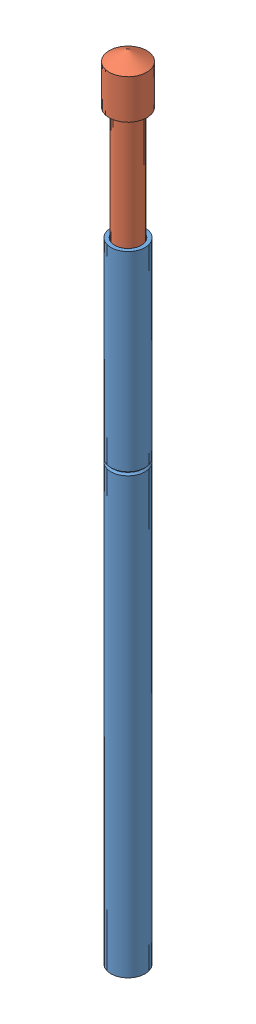
SolidWorks assembly Pin Assembly, configuration Default. Lengths in mm.
Overall size (1.57 31.69 1.57).
2 component instances, 2 part files, 2 mates.
Components (placement in the parent):
- Outer Sleeve-1: Outer Sleeve [Default] at (8.2803 2.8056 18.5203) size (1.36 25.19 1.36)
- Inner Pin-1: Inner Pin [Default] at (8.2803 16.3056 18.5203) x (0.045901 0 0.998946) z (-0.998946 0 0.045901) size (1.5 18 1.5)
Mates (geometry in assembly coordinates):
- Concentric1: concentric: cylinder of Outer Sleeve-1 through (8.2803 2.8056 18.5203) axis (0 -1 0) radius 0.53; cylinder of Inner Pin-1 through (8.2803 16.1556 18.5203) axis (0 -1 0) radius 0.5
- Distance1: distance = 4.5 mm anti-aligned: plane of Inner Pin-1 through (8.3147 32.3056 19.2695) normal (0 -1 0); plane of Outer Sleeve-1 through (8.8103 27.8056 18.5203) normal (0 1 0)
